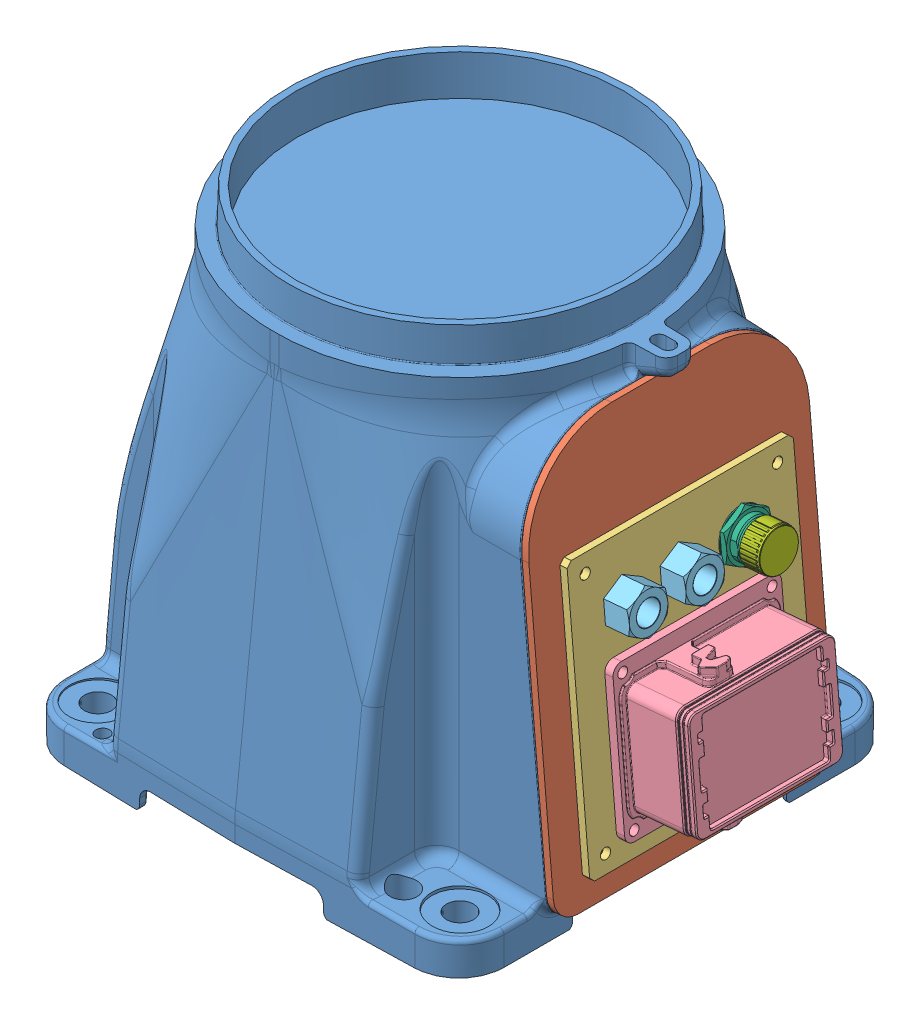
SolidWorks assembly GP7_BASE, configuration Default. Lengths in mm.
Overall size (239.06 212.52 206.8).
9 component instances, 7 part files, 0 mates.
Components (placement in the parent):
- BASE-1: BASE [Default] at origin size (201.15 212.52 206.8)
- COVER1-1: COVER1 [Default] at (101.1421 10.9249 0) x (0.996195 0.087156 0) z (-0.087156 0.996195 0) size (3 124 174)
- C_BASE_ASSEMBLY_ASM-1: C_BASE_ASSEMBLY_ASM [Default] at (97.9426 81.9162 0) x (0 0 -1) z (0.996195 0.087156 0) size (100 118 48.69)
  - C_BASE-1: C_BASE [Default] at origin size (100 118 3.2)
  - connector-1: connector [Default] at (0 -17 4.4) x (0 -1 0) z (0 0 -1) size (66.4 74.5 42.53)
  - AirInlet-1: AirInlet [Default] at (-27 34 1.4) x (0 0 -1) z (0 1 0) size (28 17 19.63)
  - LF13WBRB-20P-1: LF13WBRB-20P [Default] at (25 34 17.1) x (0 0 -1) z (1 0 0) size (19.25 23.09 21.5)
  - LF13WBR-C-1: LF13WBR-C [Default] at (25 34 12.35) x (0 0 1) z (0 1 0) size (8.8 17.9 17.9)
  - AirInlet-3: AirInlet [Default] at (-2 34 1.4) x (0 0 -1) z (0 1 0) size (28 17 19.63)
